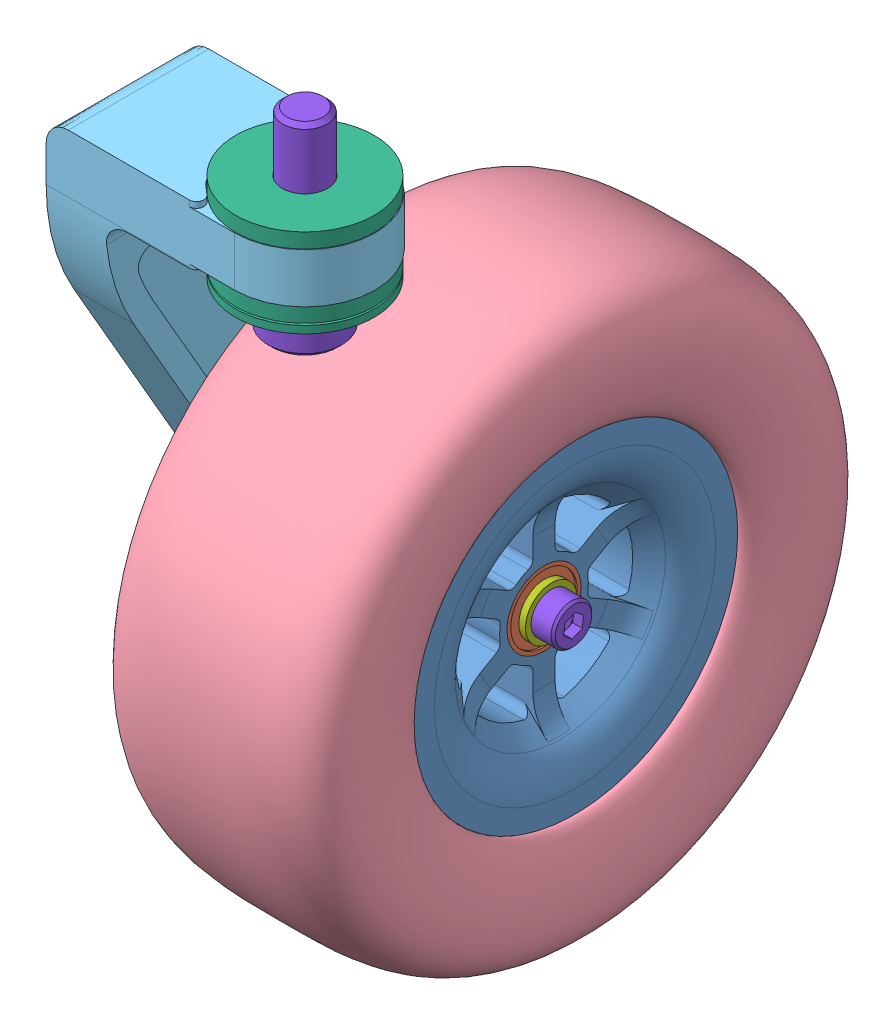
SolidWorks assembly front-wheel, configuration Default. Lengths in mm.
Overall size (45.57 103.8 77.51).
12 component instances, 8 part files, 25 mates.
Components (placement in the parent):
- front-wheel-rim-old-1: front-wheel-rim-old [Default] at origin size (24 44 44)
- bearing-10x5x4-1: bearing-10x5x4 [Default] at (17.8 0 0) x (0 -0.996096 0.088278) z (0 0.088278 0.996096) size (10 4 10)
- bearing-10x5x4-2: bearing-10x5x4 [Default] at (2 0 0) x (0 -0.086033 -0.996292) z (0 0.996292 -0.086033) size (10 4 10)
- standoff-5x20-1: standoff-5x20 [Default] at (19.9 0 0) x (0 1 0) z (0 0 1) size (5 20 5)
- front-wheel-tire-1: front-wheel-tire [Default] at origin size (41.25 77.51 77.51)
- front-caster-bottom-1: front-caster-bottom [Default] at (-0.1 0 0) x (0 0 1) z (0 -1 0) size (39.43 35 63.3)
- thrust-bearing-19x6x4-1: thrust-bearing-19x6x4 [Default] at (9.9 56 22.4275) x (0.999983 0 -0.005808) z (0.005808 0 0.999983) size (18.75 2 18.75)
- flat washer narrow_am-1: flat washer narrow_am [B18.22M - Plain washer, 3 mm, narrow] at (19.9 0 0) x (-1 0 0) z (0 0.924225 0.381849) size (0.9 7 7)
- socket head cap screw_am-1: socket head cap screw_am [B18.3.1M - 3 x 0.5 x 6 Hex SHCS -- 6NHX] at (23.8 0 0) x (-1 0 0) z (0 0.924225 0.381849) size (9 5.5 5.5)
- socket head cap screw_am-2: socket head cap screw_am [B18.3.1M - 3 x 0.5 x 8 Hex SHCS -- 8NHX] at (-15.6 0 0) size (11 5.5 5.5)
- thrust-bearing-19x6x4-2: thrust-bearing-19x6x4 [With one washer] at (9.9 47.3 22.4275) x (-0.969934 0 0.243367) z (-0.243367 0 -0.969934) size (18.75 3.25 18.75)
- socket head cap screw_am-3: socket head cap screw_am [B18.3.1M - 6 x 1.0 x 20 Hex SHCS -- 20NHX] at (9.9 39.05 22.4275) x (0 1 0) z (0 0 1) size (26 10 10)
Mates (geometry in assembly coordinates):
- Concentric1: concentric anti-aligned: cylinder of front-wheel-rim-1 through (15.8 0 0) axis (1 0 0) radius 5; cylinder of bearing-10x5x4-1 through (19.8 0 0) axis (-1 0 0) radius 5
- Coincident1: coincident anti-aligned: plane of front-wheel-rim-1 through (15.8 0 0) normal (1 0 0); plane of bearing-10x5x4-1 through (15.8 0 0) normal (-1 0 0)
- Concentric2: concentric anti-aligned: cylinder of front-wheel-rim-1 through (4 0 0) axis (-1 0 0) radius 5; cylinder of bearing-10x5x4-2 through (0 0 0) axis (1 0 0) radius 5
- Coincident3: coincident anti-aligned: plane of front-wheel-rim-1 through (4 0 0) normal (-1 0 0); plane of bearing-10x5x4-2 through (4 0 0) normal (1 0 0)
- Concentric3: concentric anti-aligned: cylinder of bearing-10x5x4-1 through (19.8 0 0) axis (-1 0 0) radius 2.5; cylinder of standoff-5x20-1 through (-0.1 0 0) axis (1 0 0) radius 2.5
- Width1: width aligned: plane of front-wheel-rim-old-1 through (19.8 12 0) normal (1 0 0); plane of standoff-5x20-1 through (0 17.125 0) normal (-1 0 0); plane of front-wheel-rim-old-1 through (19.9 0 0) normal (1 0 0); plane of standoff-5x20-1 through (-0.1 0 0) normal (-1 0 0)
- InPlace1: in place: plane of ? through (0 0 0) normal (0 0 1); moOrthogonalPlaneRef_w of ? through (0 0 0) normal (0 1 0); plane of ? through (0 0 0) normal (1 0 0); unknown of ?
- Coincident4: coincident aligned: 
- Coincident5: coincident aligned: plane of Part8^front-wheel-1 through (0 0 0) normal (0 1 0)
- Coincident6: coincident anti-aligned: plane of Part8^front-wheel-1 through (0 0 0) normal (1 0 0)
- Coincident7: coincident anti-aligned: plane of standoff-5x20-1 through (-0.1 0 0) normal (-1 0 0); plane of front-caster-bottom-1 through (-0.1 0 0) normal (1 0 0)
- Concentric4: concentric aligned: cylinder of standoff-5x20-1 through (-0.1 0 0) axis (1 0 0) radius 1.5; cylinder of front-caster-bottom-1 through (-0.6 0 0) axis (1 0 0) radius 1.6
- Coincident8: coincident anti-aligned: plane of front-caster-bottom-1 through (-0.1 0 0) normal (0 -1 0)
- Concentric5: concentric anti-aligned: cylinder of front-caster-bottom-1 through (9.9 -7.501 22.4275) axis (0 1 0) radius 3.25; cylinder of thrust-bearing-19x6x4-1 through (9.9 57 22.4275) axis (0 -1 0) radius 3.075
- Coincident9: coincident anti-aligned: plane of front-caster-bottom-1 through (9.9 55 22.4275) normal (0 1 0); plane of thrust-bearing-19x6x4-1 through (9.9 55 22.4275) normal (0 -1 0)
- Concentric6: concentric aligned: cylinder of standoff-5x20-1 through (-0.1 0 0) axis (1 0 0) radius 1.5; cylinder of flat washer narrow_am-1 through (54.825 0 0) axis (1 0 0) radius 1.84
- Coincident10: coincident anti-aligned: plane of standoff-5x20-1 through (19.9 0 0) normal (1 0 0); plane of flat washer narrow_am-1 through (19.9 -0.7026 1.7006) normal (-1 0 0)
- Concentric7: concentric aligned: cylinder of standoff-5x20-1 through (-0.1 0 0) axis (1 0 0) radius 1.5; cylinder of socket head cap screw_am-1 through (55.55 0 0) axis (1 0 0) radius 2.75
- Coincident11: coincident anti-aligned: plane of flat washer narrow_am-1 through (20.8 -1.3365 3.2348) normal (1 0 0); plane of socket head cap screw_am-1 through (20.8 -1.0501 2.5416) normal (-1 0 0)
- Concentric8: concentric anti-aligned: cylinder of front-caster-bottom-1 through (-0.6 0 0) axis (1 0 0) radius 1.6; cylinder of socket head cap screw_am-2 through (-47.35 0 0) axis (-1 0 0) radius 2.75
- Coincident12: coincident anti-aligned: plane of front-caster-bottom-1 through (-12.6 0 0) normal (-1 0 0); plane of socket head cap screw_am-2 through (-12.6 2.75 0) normal (1 0 0)
- Concentric9: concentric anti-aligned: cylinder of front-caster-bottom-1 through (9.9 -7.501 22.4275) axis (0 1 0) radius 3.25; cylinder of thrust-bearing-19x6x4-2 through (9.9 48.3 22.4275) axis (0 -1 0) radius 3.075
- Coincident14: coincident anti-aligned: plane of front-caster-bottom-1 through (9.9 48.3 22.4275) normal (0 -1 0); plane of thrust-bearing-19x6x4-2 through (9.9 48.3 22.4275) normal (0 1 0)
- Concentric11: concentric anti-aligned: cylinder of thrust-bearing-19x6x4-2 through (9.9 45.05 22.4275) axis (0 1 0) radius 3.075; cylinder of socket head cap screw_am-3 through (9.9 7.3 22.4275) axis (0 -1 0) radius 5
- Coincident15: coincident anti-aligned: plane of thrust-bearing-19x6x4-2 through (9.9 45.05 22.4275) normal (0 -1 0); plane of socket head cap screw_am-3 through (4.9 45.05 22.4275) normal (0 1 0)
